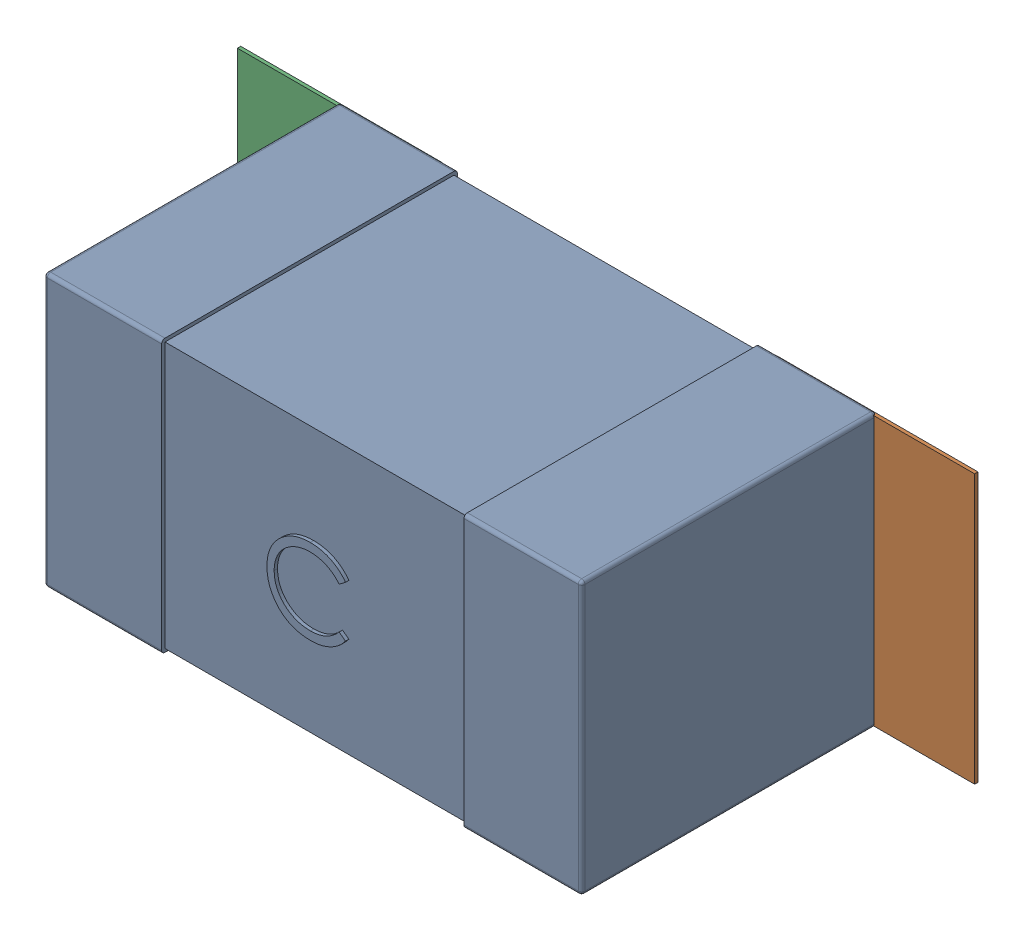
SolidWorks assembly C34, configuration Défaut. Lengths in mm.
Overall size (2.19 0.81 0.88).
5 component instances, 2 part files, 0 mates.
Components (placement in the parent):
- 0603_C-1: 0603_C [Défaut] at (8.9379 -13.0211 0) x (1 0 0) z (0 0 1) size (1.6 0.81 0.88)
- 6634915696-1: 6634915696 [Défaut] at (10.1879 -13.0211 0) size (0.6 0.8 0.01)
  - Extruded_497-1: Extruded_497 [Défaut] at origin size (0.6 0.8 0.01)
- 6634915696-2: 6634915696 [Défaut] at (8.593 -13.0211 0) size (0.6 0.8 0.01)
  - Extruded_497-1: Extruded_497 [Défaut] at origin size (0.6 0.8 0.01)
